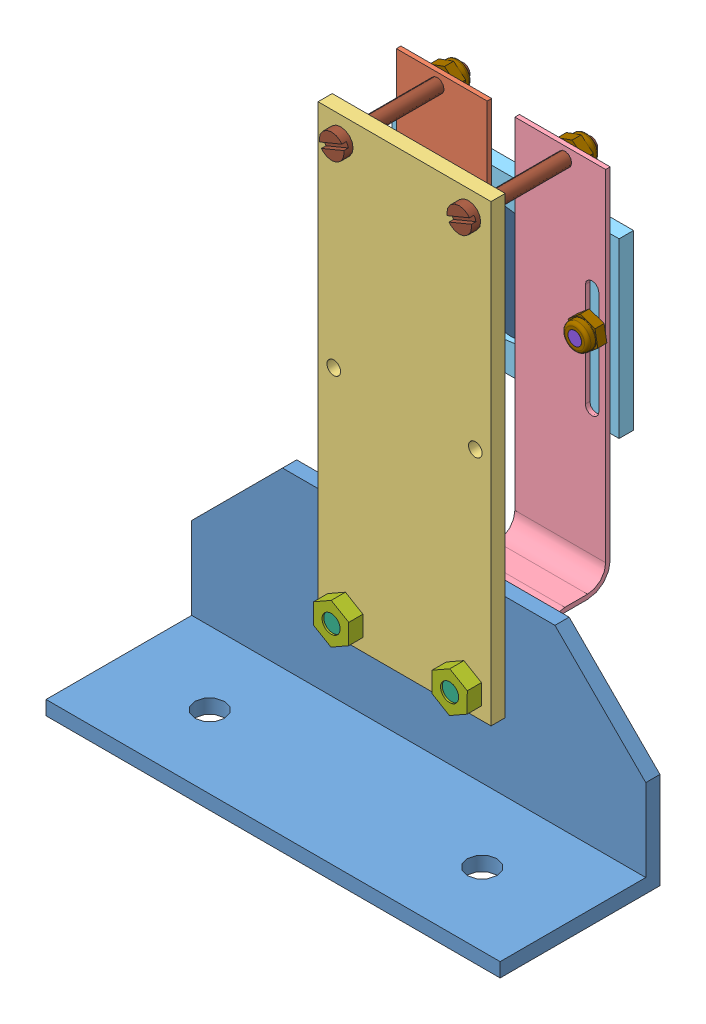
SolidWorks assembly Suporte do Espelho Fixo, configuration Default. Lengths in mm.
Overall size (100 118.13 56.38).
18 component instances, 11 part files, 37 mates.
Components (placement in the parent):
- Base do esplho fixo-1: Base do esplho fixo [Default] at (-53.8426 -5.3532 32.0489) size (100 41.23 35.2)
- Mola chata-1: Mola chata [Default] at (-6.8926 7.1468 -4.1491) x (0 0 1) z (0 -1 0) size (16 20 100)
- Coluna-1: Coluna [Default] at (15.2074 34.6468 -0.0241) size (38.1 100 3.12)
- Mola chata_espelhada-1: Mola chata_espelhada [Default] at (19.2074 7.1468 -4.1491) x (0 0 1) z (0 -1 0) size (16 20 100)
- Suporte do Espelho-1: Suporte do Espelho [Default] at (-28.8426 56.3037 -19.1491) x (0 -1 0) z (0 0 1) size (38.1 50 3.18)
- Parafuso Padrao M4 16-1: Parafuso Padrao M4 16 [Default] at (-16.8926 14.6468 -4.1491) x (1 0 0) z (0 1 0) size (8 13 8)
- Parafuso Padrao M4 16-2: Parafuso Padrao M4 16 [Default] at (9.2074 14.6468 -4.1491) x (1 0 0) z (0 1 0) size (8 13 8)
- Porca M4-1: Porca M4 [Default] at (9.2074 14.6468 6.2259) x (1 0 0) z (0 1 0) size (7.78 3.12 8.95)
- Porca M4-2: Porca M4 [Default] at (-16.8926 14.6468 6.2259) x (1 0 0) z (0 1 0) size (7.78 3.12 8.95)
- Parafuso Padrao M3 10-1: Parafuso Padrao M3 10 [Default] at (-24.3517 75.3537 -24.3291) x (-0.944047 -0.32981 0) z (0 0 1) size (5.45 5.45 14)
- Parafuso Padrao M3 10-2: Parafuso Padrao M3 10 [Default] at (16.2074 75.3537 -24.3291) size (5.45 5.45 14)
- Porca M3-1: Porca M3 [Default] at (16.2074 75.3537 -18.1491) x (1 0 0) z (0 -1 0) size (6.52 3.8 6.82)
- Porca M3-2: Porca M3 [Default] at (-24.3517 75.3537 -18.1491) x (0.940985 0.338447 0) z (0.338447 -0.940985 0) size (6.52 3.8 6.82)
- Espelho-1: Espelho [Default] at (-3.8426 75.3537 -23.3291) size (25.4 25.4 3)
- Parafuso Padrao M3 20-1: Parafuso Padrao M3 20 [Default] at (-17.8926 104.6468 5.1009) x (-0.923728 -0.383049 0) z (0 0 -1) size (5.45 5.45 22)
- Parafuso Padrao M3 20-2: Parafuso Padrao M3 20 [Default] at (10.2074 104.6468 5.1009) x (-0.923728 -0.383049 0) z (0 0 -1) size (5.45 5.45 22)
- Porca M3-3: Porca M3 [Default] at (10.2074 104.6468 -19.1491) x (1 0 0) z (0 1 0) size (6.52 3.8 6.82)
- Porca M3-4: Porca M3 [Default] at (-17.8926 104.6468 -19.1491) x (1 0 0) z (0 1 0) size (6.52 3.8 6.82)
Mates (geometry in assembly coordinates):
- Concentric1: concentric anti-aligned: cylinder of Base do esplho fixo-1 through (-16.8926 14.6468 32.0489) axis (0 0 -1) radius 2; cylinder of Mola chata-1 through (-16.8926 14.6468 -19.1491) axis (0 0 1) radius 2
- Coincident1: coincident anti-aligned: plane of Base do esplho fixo-1 through (46.1574 -5.3532 -3.1491) normal (0 0 -1); plane of Mola chata-1 through (-26.8926 7.1468 -3.1491) normal (0 0 1)
- Parallel1: parallel aligned: plane of Base do esplho fixo-1 through (-53.8426 -5.3532 -3.1491) normal (-1 0 0); plane of Mola chata-1 through (-26.8926 32.1468 -14.1491) normal (-1 0 0)
- Coincident6: coincident anti-aligned: plane of Base do esplho fixo-1 through (46.1574 -5.3532 -0.0241) normal (0 0 1); plane of Coluna-1 through (15.2074 109.6468 -0.0241) normal (0 0 -1)
- Parallel3: parallel aligned: plane of Base do esplho fixo-1 through (-53.8426 -5.3532 -3.1491) normal (-1 0 0); plane of Coluna-1 through (-22.8926 34.6468 3.1009) normal (-1 0 0)
- Concentric3: concentric anti-aligned: cylinder of Base do esplho fixo-1 through (-16.8926 14.6468 32.0489) axis (0 0 -1) radius 2; circle of Coluna-1
- Coincident9: coincident anti-aligned: plane of Base do esplho fixo-1 through (46.1574 -5.3532 -3.1491) normal (0 0 -1); plane of Mola chata_espelhada-1 through (-0.7926 7.1468 -3.1491) normal (0 0 1)
- Concentric4: concentric anti-aligned: cylinder of Base do esplho fixo-1 through (9.2074 14.6468 32.0489) axis (0 0 -1) radius 2; cylinder of Mola chata_espelhada-1 through (9.2074 14.6468 -19.1491) axis (0 0 1) radius 2
- Parallel4: parallel aligned: plane of Base do esplho fixo-1 through (46.1574 -5.3532 -3.1491) normal (1 0 0); plane of Mola chata_espelhada-1 through (19.2074 32.1468 -14.1491) normal (1 0 0)
- Coincident11: coincident anti-aligned: plane of Mola chata_espelhada-1 through (-0.7926 32.1468 -19.1491) normal (0 0 -1); plane of Suporte do Espelho-1 through (21.1574 56.3037 -19.1491) normal (0 0 1)
- Distance1: distance = 1.95 mm aligned: plane of Mola chata_espelhada-1 through (19.2074 32.1468 -14.1491) normal (1 0 0); plane of Suporte do Espelho-1 through (21.1574 56.3037 -22.3291) normal (1 0 0)
- Concentric5: concentric aligned: cylinder of Base do esplho fixo-1 through (-16.8926 14.6468 32.0489) axis (0 0 -1) radius 2; cylinder of Parafuso Padrao M4 16-1 through (-16.8926 14.6468 5.8509) axis (0 0 -1) radius 2
- Coincident13: coincident anti-aligned: plane of Mola chata-1 through (-26.8926 7.1468 -4.1491) normal (0 0 -1); plane of Parafuso Padrao M4 16-1 through (-16.8926 14.6468 -4.1491) normal (0 0 1)
- Concentric6: concentric anti-aligned: cylinder of Coluna-1 through (9.2074 14.6468 -0.0241) axis (0 0 1) radius 2; cylinder of Parafuso Padrao M4 16-2 through (9.2074 14.6468 5.8509) axis (0 0 -1) radius 2
- Coincident15: coincident anti-aligned: plane of Parafuso Padrao M4 16-2 through (9.2074 14.6468 -4.1491) normal (0 0 1); plane of Mola chata_espelhada-1 through (-0.7926 7.1468 -4.1491) normal (0 0 -1)
- Concentric7: concentric anti-aligned: cylinder of Parafuso Padrao M4 16-2 through (9.2074 14.6468 5.8509) axis (0 0 -1) radius 2; cylinder of Porca M4-1 through (9.2074 14.6468 3.1009) axis (0 0 1) radius 2
- Coincident16: coincident anti-aligned: plane of Coluna-1 through (15.2074 109.6468 3.1009) normal (0 0 1); plane of Porca M4-1 through (13.0978 16.8572 3.1009) normal (0 0 -1)
- Concentric8: concentric anti-aligned: cylinder of Parafuso Padrao M4 16-1 through (-16.8926 14.6468 5.8509) axis (0 0 -1) radius 2; cylinder of Porca M4-2 through (-16.8926 14.6468 3.1009) axis (0 0 1) radius 2
- Coincident18: coincident anti-aligned: plane of Coluna-1 through (15.2074 109.6468 3.1009) normal (0 0 1); plane of Porca M4-2 through (-13.0022 16.8572 3.1009) normal (0 0 -1)
- Coincident19: coincident anti-aligned: plane of Suporte do Espelho-1 through (21.1574 94.4037 -22.3291) normal (0 0 -1); plane of Parafuso Padrao M3 10-1 through (-24.3517 75.3537 -22.3291) normal (0 0 1)
- Coincident20: coincident anti-aligned: plane of Suporte do Espelho-1 through (21.1574 94.4037 -22.3291) normal (0 0 -1); plane of Parafuso Padrao M3 10-2 through (16.2074 75.3537 -22.3291) normal (0 0 1)
- Concentric11: concentric anti-aligned: cylinder of Parafuso Padrao M3 10-2 through (16.2074 75.3537 -10.3291) axis (0 0 -1) radius 1.5; cylinder of Porca M3-1 through (16.2074 75.3537 -18.1491) axis (0 0 1) radius 1.5
- Coincident21: coincident anti-aligned: plane of Mola chata_espelhada-1 through (-0.7926 32.1468 -18.1491) normal (0 0 1); plane of Porca M3-1 through (20.0777 70.7689 -18.1491) normal (0 0 -1)
- Concentric12: concentric anti-aligned: cylinder of Parafuso Padrao M3 10-1 through (-24.3517 75.3537 -10.3291) axis (0 0 -1) radius 1.5; cylinder of Porca M3-2 through (-24.3517 75.3537 -18.1491) axis (0 0 1) radius 1.5
- Coincident22: coincident: plane of Mola chata-1 through (-26.8926 32.1468 -18.1491) normal (0 0 1); moEndPointRef_w of Porca M3-2
- Concentric13: concentric anti-aligned: cylinder of Suporte do Espelho-1 through (-3.8426 75.3537 -22.3291) axis (0 0 1) radius 12.7; cylinder of Espelho-1 through (-3.8426 75.3537 -20.3291) axis (0 0 -1) radius 12.7
- Distance2: distance = 1 mm aligned: plane of Suporte do Espelho-1 through (21.1574 94.4037 -22.3291) normal (0 0 -1); plane of Espelho-1 through (-3.8426 75.3537 -23.3291) normal (0 0 -1)
- Coincident24: coincident aligned: circle of Coluna-1; cylinder of Parafuso Padrao M3 20-1 through (-17.8926 104.6468 -16.8991) axis (0 0 1) radius 1.5
- Coincident25: coincident anti-aligned: plane of Coluna-1 through (15.2074 109.6468 3.1009) normal (0 0 1); plane of Parafuso Padrao M3 20-1 through (-17.8926 104.6468 3.1009) normal (0 0 -1)
- Concentric14: concentric aligned: circle of Coluna-1; cylinder of Parafuso Padrao M3 20-2 through (10.2074 104.6468 -16.8991) axis (0 0 1) radius 1.5
- Coincident27: coincident anti-aligned: plane of Coluna-1 through (15.2074 109.6468 3.1009) normal (0 0 1); circle of Parafuso Padrao M3 20-2
- Concentric15: concentric anti-aligned: cylinder of Parafuso Padrao M3 20-2 through (10.2074 104.6468 -16.8991) axis (0 0 1) radius 1.5; circle of Porca M3-3
- Coincident29: coincident anti-aligned: plane of Mola chata_espelhada-1 through (-0.7926 32.1468 -19.1491) normal (0 0 -1); plane of Porca M3-3 through (14.0777 109.2316 -19.1491) normal (0 0 1)
- Concentric16: concentric anti-aligned: cylinder of Parafuso Padrao M3 20-1 through (-17.8926 104.6468 -16.8991) axis (0 0 1) radius 1.5; cylinder of Porca M3-4 through (-17.8926 104.6468 -19.1491) axis (0 0 -1) radius 1.5
- Coincident30: coincident anti-aligned: plane of Mola chata-1 through (-26.8926 32.1468 -19.1491) normal (0 0 -1); plane of Porca M3-4 through (-14.0223 109.2316 -19.1491) normal (0 0 1)
- Concentric17: concentric anti-aligned: cylinder of Suporte do Espelho-1 through (-24.3517 75.3537 -22.3291) axis (0 0 1) radius 1.5; cylinder of Parafuso Padrao M3 10-1 through (-24.3517 75.3537 -10.3291) axis (0 0 -1) radius 1.5
- Concentric18: concentric anti-aligned: cylinder of Suporte do Espelho-1 through (16.2074 75.3537 -22.3291) axis (0 0 1) radius 1.5; cylinder of Parafuso Padrao M3 10-2 through (16.2074 75.3537 -10.3291) axis (0 0 -1) radius 1.5
